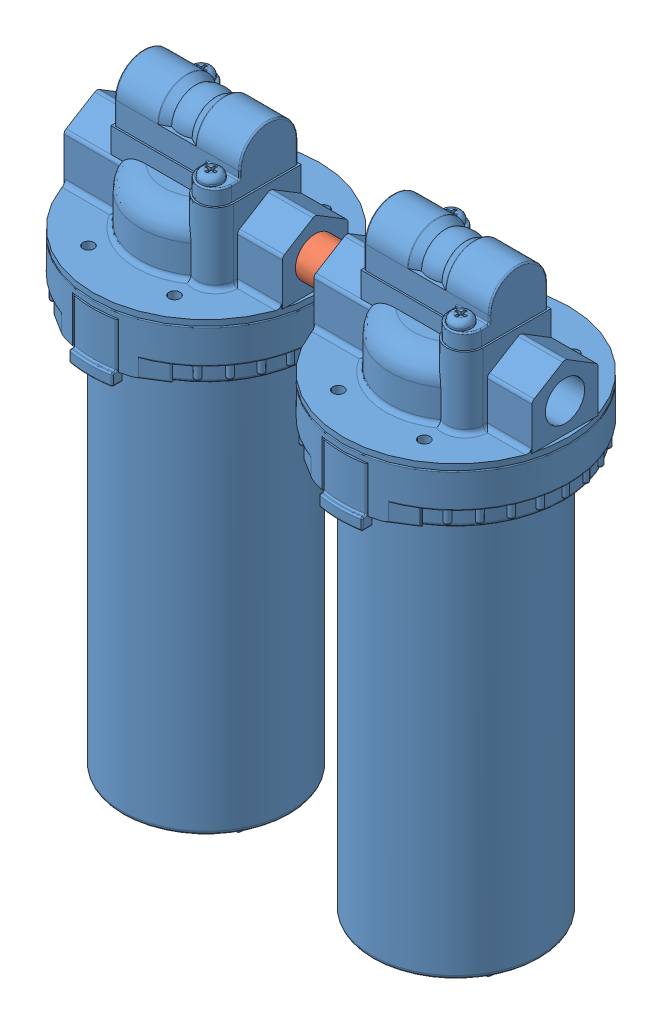
SolidWorks assembly ReadingTech_4P-060-M03-DCPi, configuration Default. Lengths in mm.
Overall size (206.63 271.65 99.95).
3 component instances, 2 part files, 3 mates.
Components (placement in the parent):
- ReadingTech_3P-060-M03-Pi-1: ReadingTech_3P-060-M03-Pi [Default] at (-45.8012 -102.2072 10.6205) size (98.17 271.65 99.95)
- ReadingTech_3P-060-M03-Pi-2: ReadingTech_3P-060-M03-Pi [Default] at (62.6568 -102.2072 10.6205) size (98.17 271.65 99.95)
- ReadingTech- 60cfm_connector_.375in-1: ReadingTech- 60cfm_connector_.375in [Default] at (15.2858 113.6928 10.6205) x (0 1 0) z (0 0 1) size (17.14 13.72 17.14)
Mates (geometry in assembly coordinates):
- Coincident1: coincident anti-aligned: circle of ReadingTech_3P-060-M03-Pi-1; circle of ReadingTech- 60cfm_connector_.375in-1
- Coincident2: coincident aligned: circle of ReadingTech_3P-060-M03-Pi-2; circle of ReadingTech- 60cfm_connector_.375in-1
- Coincident3: coincident aligned: plane of ReadingTech_3P-060-M03-Pi-1 through (1.5698 100.9928 24.908) normal (0 0 1); plane of ReadingTech_3P-060-M03-Pi-2 through (110.0278 100.9928 24.908) normal (0 0 1)
